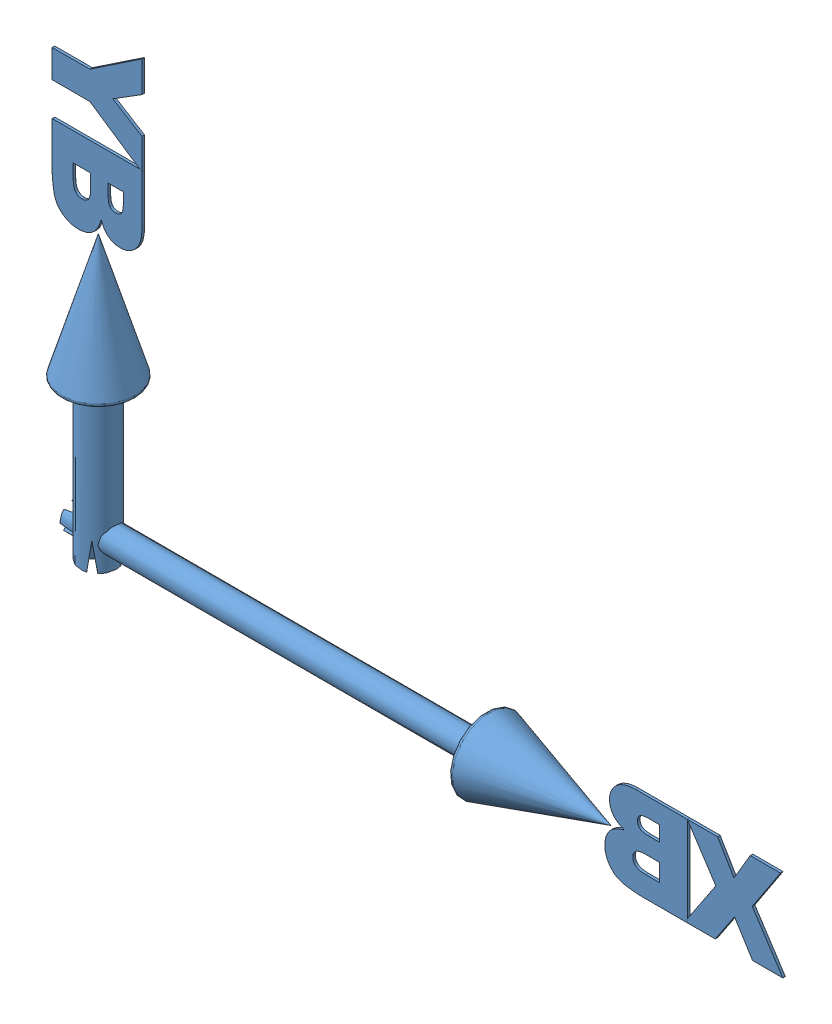
SolidWorks assembly B1995, configuration woLabels. Lengths in mm.
Overall size (239.39 157.62 264.32).
4 component instances, 2 part files, 1 mates.
Components (placement in the parent):
- B1998-1: B1998 [X] x (0 0 -1) z (1 0 0) size (28.64 28.64 210)
- B1998-2: B1998 [Y] x (0 0 1) z (0 1 0) size (28.64 28.64 110)
- B1998-3: B1998 [Z] at origin size (28.64 28.64 260)
- B1999-2: B1999 [100] at (0 0 197.2124) x (0 0 -1) z (0.268665 -0.963234 0)
Mates (geometry in assembly coordinates):
- Concentric1: concentric aligned: cylinder of B1998-3 through (0 0 250) axis (0 0 1) radius 3; cylinder of B1999-2 through (0 0 197.2124) axis (0 0 1) radius 50
